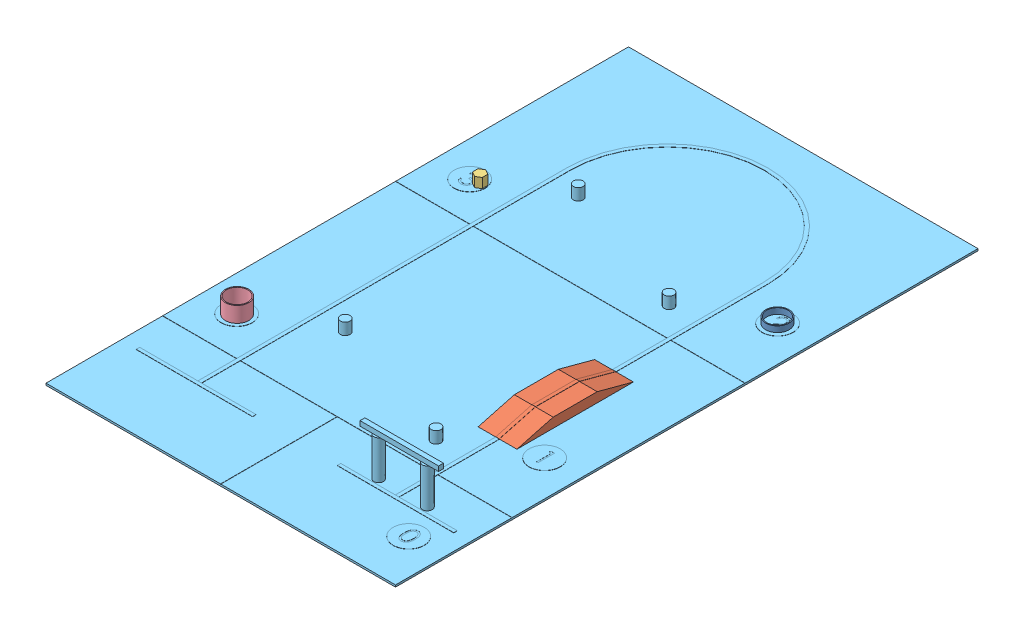
SolidWorks assembly Test Place, configuration 預設. Lengths in mm.
Overall size (1800 235 3000).
6 component instances, 6 part files, 0 mates.
Components (placement in the parent):
- Ball Bucket 1-1: Ball Bucket 1 [Default] at (717.4068 1.6554 -1749.596) size (120 30 120)
- Hill-1: Hill [Default] at (508.2919 0.7332 -517.1834) x (0 0 -1) z (1 0 0) size (600.52 51 200)
- Hexagonal-1: Hexagonal [Default] at (-667.9429 1 -1603.7384) x (0.876055 0 0.482211) z (-0.482211 0 0.876055) size (57.74 50 50)
- Ball-1: Ball [預設] at (507.5568 37.3778 66.0375) size (39 39 39) (hidden)
- Ball Bucket 2-2: Ball Bucket 2 [預設] at (-715.465 1.322 -399.5913) size (120 80 120)
- Track-2: Track [Default] at origin size (1800 235 3000)
